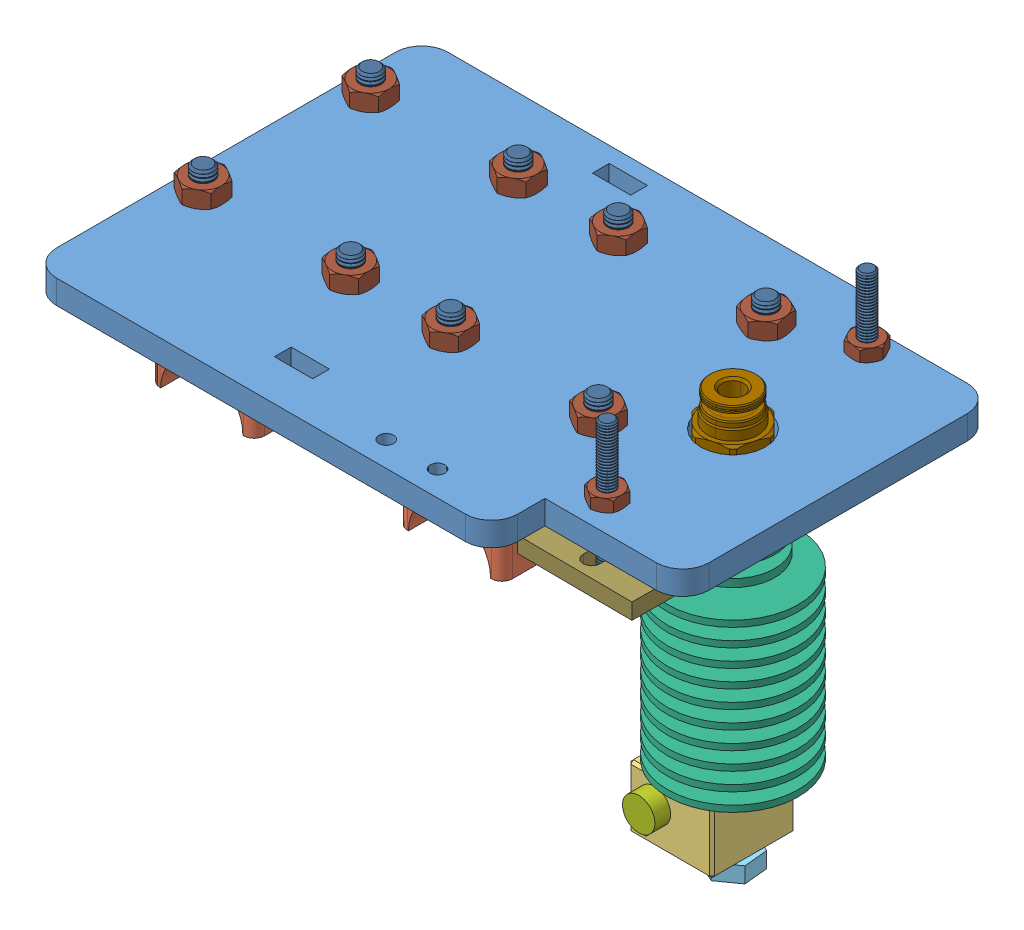
SolidWorks assembly print head assembly, configuration Default. Lengths in mm.
Overall size (114.36 87.96 74.73).
34 component instances, 12 part files, 60 mates.
Components (placement in the parent):
- mounting plate-1: mounting plate [Default] at (-11.5996 63.3996 119.5464) size (114.36 4.55 74.73)
- bearing housing-1: bearing housing [Default] at (17.6504 63.3996 74.0664) x (-1 0 0) z (0 0 1) size (38.1 17.15 28.7)
- bearing housing-2: bearing housing [Default] at (17.6504 63.3996 106.0664) x (-1 0 0) z (0 0 1) size (38.1 17.15 28.7)
- bearing housing-3: bearing housing [Default] at (64.9504 63.3996 74.0664) x (-1 0 0) z (0 0 1) size (38.1 17.15 28.7)
- bearing housing-4: bearing housing [Default] at (64.9504 63.3996 106.0664) x (-1 0 0) z (0 0 1) size (38.1 17.15 28.7)
- E3D-1: E3D [Default] at (78.8704 -0.8004 79.8564) x (-1 0 0) z (0 0 -1) size (28.79 69.7 28.79)
  - E3D Heat Block-1: E3D Heat Block [Default] at origin size (16 12 16)
  - E3D Heatbreak-1: E3D Heatbreak [Default] at (-4 19.55 0) x (-0.93266 0 -0.360757) z (-0.360757 0 0.93266) size (6 25.1 6)
  - E3D Nozzle-1: E3D Nozzle [Default] at (-4 -3.5 0) x (-0.097107 0 -0.995274) z (0.995274 0 -0.097107) size (9.24 12.5 8)
  - E3D Heatsink-1: E3D Heatsink [1.75 Bowden] at (-4 39.15 0) x (0.986263 0 -0.165183) z (0.165183 0 0.986263) size (25 50.1 25)
  - cartridge heater-1: cartridge heater [Default] at (3 7 0) x (0 0 1) z (-0.150948 -0.988542 0) size (32 6.2 6.2)
  - thermistor-1: thermistor [Default] at (-6 2 6.5) x (-0.997586 0.069447 0) z (-0.069447 -0.997586 0) size (2 13.25 2)
- PB156_1_8-1: PB156_1_8 [Default] at (82.8704 63.7223 79.8564) x (0 -1 0) z (0.258692 0 0.96596) size (19.6 12.3 13.69)
- socket head cap screw_am-6: socket head cap screw_am [B18.3.1M - 4 x 0.7 x 16 Hex SHCS -- 16SHX] at (69.0504 53.0996 59.7164) x (0 1 0) z (-0.973946 0 -0.226779) size (20 7 7)
- socket head cap screw_am-7: socket head cap screw_am [B18.3.1M - 4 x 0.7 x 16 Hex SHCS -- 16SHX] at (69.0504 53.0996 91.7164) x (0 1 0) z (0 0 1) size (20 7 7)
- socket head cap screw_am-8: socket head cap screw_am [B18.3.1M - 4 x 0.7 x 16 Hex SHCS -- 16SHX] at (21.7504 53.0996 91.7164) x (0 1 0) z (0 0 1) size (20 7 7)
- socket head cap screw_am-9: socket head cap screw_am [B18.3.1M - 4 x 0.7 x 16 Hex SHCS -- 16SHX] at (21.7504 53.0996 59.7164) x (0 1 0) z (0 0 1) size (20 7 7)
- socket head cap screw_am-10: socket head cap screw_am [B18.3.1M - 4 x 0.7 x 16 Hex SHCS -- 16SHX] at (40.8504 53.0996 91.7164) x (0 1 0) z (0 0 1) size (20 7 7)
- socket head cap screw_am-11: socket head cap screw_am [B18.3.1M - 4 x 0.7 x 16 Hex SHCS -- 16SHX] at (-6.4496 53.0996 91.7164) x (0 1 0) z (0 0 1) size (20 7 7)
- socket head cap screw_am-12: socket head cap screw_am [B18.3.1M - 4 x 0.7 x 16 Hex SHCS -- 16SHX] at (-6.4496 53.0996 59.7164) x (0 1 0) z (0 0 1) size (20 7 7)
- socket head cap screw_am-13: socket head cap screw_am [B18.3.1M - 4 x 0.7 x 16 Hex SHCS -- 16SHX] at (40.8504 53.0996 59.7164) x (0 1 0) z (0 0 1) size (20 7 7)
- hex nut style 1_am-1: hex nut style 1_am [B18.2.4.1M - Hex nut, Style 1,  M4 x 0.7 --D-N] at (69.0504 67.9496 59.7164) x (0.615546 0 0.788101) z (0 -1 0) size (7 8.08 3.2)
- hex nut style 1_am-2: hex nut style 1_am [B18.2.4.1M - Hex nut, Style 1,  M4 x 0.7 --D-N] at (69.0504 71.1496 91.7164) x (1 0 0) z (0 1 0) size (7 8.08 3.2)
- hex nut style 1_am-3: hex nut style 1_am [B18.2.4.1M - Hex nut, Style 1,  M4 x 0.7 --D-N] at (40.8504 71.1496 91.7164) x (1 0 0) z (0 1 0) size (7 8.08 3.2)
- hex nut style 1_am-4: hex nut style 1_am [B18.2.4.1M - Hex nut, Style 1,  M4 x 0.7 --D-N] at (21.7504 71.1496 91.7164) x (1 0 0) z (0 1 0) size (7 8.08 3.2)
- hex nut style 1_am-5: hex nut style 1_am [B18.2.4.1M - Hex nut, Style 1,  M4 x 0.7 --D-N] at (-6.4496 71.1496 91.7164) x (1 0 0) z (0 1 0) size (7 8.08 3.2)
- hex nut style 1_am-6: hex nut style 1_am [B18.2.4.1M - Hex nut, Style 1,  M4 x 0.7 --D-N] at (-6.4496 71.1496 59.7164) x (1 0 0) z (0 1 0) size (7 8.08 3.2)
- hex nut style 1_am-7: hex nut style 1_am [B18.2.4.1M - Hex nut, Style 1,  M4 x 0.7 --D-N] at (21.7504 71.1496 59.7164) x (1 0 0) z (0 1 0) size (7 8.08 3.2)
- hex nut style 1_am-8: hex nut style 1_am [B18.2.4.1M - Hex nut, Style 1,  M4 x 0.7 --D-N] at (40.8504 71.1496 59.7164) x (1 0 0) z (0 1 0) size (7 8.08 3.2)
- hotend bracket-1: hotend bracket [Default] at (93.6576 56.6596 109.9336) x (0.007083 0 -0.999975) z (0.999975 0 0.007083) size (60 3.04 22)
- socket head cap screw_am-14: socket head cap screw_am [B18.3.1M - 3 x 0.5 x 25 Hex SHCS -- 25SHX] at (82.8504 53.6596 54.2164) x (0 1 0) z (0 0 1) size (28 5.5 5.5)
- socket head cap screw_am-15: socket head cap screw_am [B18.3.1M - 3 x 0.5 x 25 Hex SHCS -- 25SHX] at (82.8504 53.6596 103.8564) x (0 1 0) z (-0.007083 0 0.999975) size (28 5.5 5.5)
- hex nut style 1_am-9: hex nut style 1_am [B18.2.4.1M - Hex nut, Style 1,  M3 x 0.5 --D-N] at (82.8504 67.9496 54.2164) x (0.837169 0 0.546944) z (0 -1 0) size (5.5 6.35 2.4)
- hex nut style 1_am-10: hex nut style 1_am [B18.2.4.1M - Hex nut, Style 1,  M3 x 0.5 --D-N] at (82.8504 70.3496 103.8564) x (1 0 0) z (0 1 0) size (5.5 6.35 2.4)
Mates (geometry in assembly coordinates):
- Coincident2: coincident anti-aligned: plane of mounting plate-1 through (97.7604 63.3996 104.3464) normal (0 -1 0); plane of bearing housing-2 through (17.6504 63.3996 106.0664) normal (0 1 0)
- Coincident3: coincident anti-aligned: plane of mounting plate-1 through (97.7604 63.3996 104.3464) normal (0 -1 0); plane of bearing housing-1 through (17.6504 63.3996 74.0664) normal (0 1 0)
- Coincident4: coincident anti-aligned: plane of mounting plate-1 through (97.7604 63.3996 104.3464) normal (0 -1 0); plane of bearing housing-4 through (64.9504 63.3996 106.0664) normal (0 1 0)
- Coincident5: coincident anti-aligned: plane of mounting plate-1 through (97.7604 63.3996 104.3464) normal (0 -1 0); plane of bearing housing-3 through (64.9504 63.3996 74.0664) normal (0 1 0)
- Concentric9: concentric anti-aligned: circle of mounting plate-1; cylinder of bearing housing-3 through (40.8504 57.0996 59.7164) axis (0 -1 0) radius 2.4
- Concentric10: concentric aligned: cylinder of mounting plate-1 through (40.8504 67.9496 91.7164) axis (0 -1 0) radius 2.15; cylinder of bearing housing-4 through (40.8504 57.0996 91.7164) axis (0 -1 0) radius 2.4
- Concentric11: concentric anti-aligned: circle of mounting plate-1; cylinder of bearing housing-4 through (69.0504 57.0996 91.7164) axis (0 -1 0) radius 2.4
- Concentric12: concentric anti-aligned: circle of mounting plate-1; circle of bearing housing-3
- Concentric13: concentric aligned: cylinder of mounting plate-1 through (21.7504 67.9496 91.7164) axis (0 -1 0) radius 2.15; circle of bearing housing-2
- Concentric14: concentric aligned: cylinder of mounting plate-1 through (-6.4496 67.9496 91.7164) axis (0 -1 0) radius 2.15; circle of bearing housing-2
- Concentric15: concentric aligned: cylinder of mounting plate-1 through (21.7504 67.9496 59.7164) axis (0 -1 0) radius 2.15; cylinder of bearing housing-1 through (21.7504 57.0996 59.7164) axis (0 -1 0) radius 2.4
- Concentric16: concentric aligned: cylinder of mounting plate-1 through (-6.4496 67.9496 59.7164) axis (0 -1 0) radius 2.15; cylinder of bearing housing-1 through (-6.4496 57.0996 59.7164) axis (0 -1 0) radius 2.4
- Concentric17: concentric aligned: cylinder of mounting plate-1 through (82.8704 67.9496 79.8564) axis (0 -1 0) radius 6.15; cylinder of E3D-1/E3D Heatsink-1 through (82.8704 13.2996 79.8564) axis (0 -1 0) radius 6
- Parallel1: parallel aligned: plane of mounting plate-1 through (102.7604 67.9496 104.3464) normal (1 0 0); plane of E3D-1/E3D Heat Block-1 through (86.8704 11.1996 71.8564) normal (1 0 0)
- Coincident7: coincident anti-aligned: plane of mounting plate-1 through (97.7604 63.3996 104.3464) normal (0 -1 0); plane of E3D-1/E3D Heatsink-1 through (78.0731 63.3996 80.6599) normal (0 1 0)
- Concentric18: concentric aligned: cylinder of E3D-1/E3D Heatsink-1 through (82.8704 13.2996 79.8564) axis (0 -1 0) radius 4.8641; cone of PB156_1_8-1 through (82.8704 63.7223 79.8564) axis (0 -1 0)
- Coincident8: coincident: circle of E3D-1/E3D Heatsink-1; cone of PB156_1_8-1 through (82.8704 64.2405 79.8564) axis (0 -1 0)
- Concentric22: concentric aligned: cylinder of bearing housing-4 through (69.0504 57.0996 91.7164) axis (0 -1 0) radius 2.4; cylinder of socket head cap screw_am-7 through (69.0504 21.3496 91.7164) axis (0 -1 0) radius 3.5
- Coincident12: coincident anti-aligned: plane of bearing housing-4 through (68.2397 57.0996 85.6864) normal (0 -1 0); plane of socket head cap screw_am-7 through (65.5504 57.0996 91.7164) normal (0 1 0)
- Concentric23: concentric aligned: cylinder of bearing housing-2 through (21.7504 57.0996 91.7164) axis (0 -1 0) radius 2.4; cylinder of socket head cap screw_am-8 through (21.7504 21.3496 91.7164) axis (0 -1 0) radius 3.5
- Coincident13: coincident anti-aligned: plane of bearing housing-2 through (20.9397 57.0996 85.6864) normal (0 -1 0); plane of socket head cap screw_am-8 through (18.2504 57.0996 91.7164) normal (0 1 0)
- Concentric241: concentric aligned: cylinder of bearing housing-1 through (21.7504 57.0996 59.7164) axis (0 -1 0) radius 2.4; cylinder of socket head cap screw_am-9 through (21.7504 21.3496 59.7164) axis (0 -1 0) radius 3.5
- Coincident141: coincident anti-aligned: plane of bearing housing-1 through (20.9397 57.0996 53.6864) normal (0 -1 0); plane of socket head cap screw_am-9 through (18.2504 57.0996 59.7164) normal (0 1 0)
- Concentric25: concentric aligned: cylinder of bearing housing-4 through (40.8504 57.0996 91.7164) axis (0 -1 0) radius 2.4; cylinder of socket head cap screw_am-10 through (40.8504 21.3496 91.7164) axis (0 -1 0) radius 3.5
- Coincident15: coincident anti-aligned: plane of bearing housing-4 through (41.6611 57.0996 85.6864) normal (0 -1 0); plane of socket head cap screw_am-10 through (37.3504 57.0996 91.7164) normal (0 1 0)
- Concentric26: concentric aligned: cylinder of bearing housing-2 through (-6.4496 57.0996 91.7164) axis (0 -1 0) radius 2.4; cylinder of socket head cap screw_am-11 through (-6.4496 21.3496 91.7164) axis (0 -1 0) radius 3.5
- Coincident16: coincident anti-aligned: plane of bearing housing-2 through (-5.6389 57.0996 85.6864) normal (0 -1 0); plane of socket head cap screw_am-11 through (-9.9496 57.0996 91.7164) normal (0 1 0)
- Concentric27: concentric aligned: cylinder of bearing housing-1 through (-6.4496 57.0996 59.7164) axis (0 -1 0) radius 2.4; cylinder of socket head cap screw_am-12 through (-6.4496 21.3496 59.7164) axis (0 -1 0) radius 3.5
- Coincident17: coincident anti-aligned: plane of bearing housing-1 through (-5.6389 57.0996 53.6864) normal (0 -1 0); plane of socket head cap screw_am-12 through (-9.9496 57.0996 59.7164) normal (0 1 0)
- Concentric28: concentric aligned: cylinder of bearing housing-3 through (40.8504 57.0996 59.7164) axis (0 -1 0) radius 2.4; cylinder of socket head cap screw_am-13 through (40.8504 21.3496 59.7164) axis (0 -1 0) radius 3.5
- Coincident18: coincident anti-aligned: plane of bearing housing-3 through (41.6611 57.0996 53.6864) normal (0 -1 0); plane of socket head cap screw_am-13 through (37.3504 57.0996 59.7164) normal (0 1 0)
- Concentric29: concentric aligned: circle of bearing housing-3; circle of socket head cap screw_am-6
- Coincident19: coincident anti-aligned: plane of bearing housing-3 through (68.2397 57.0996 53.6864) normal (0 -1 0); plane of socket head cap screw_am-6 through (69.8441 57.0996 56.3076) normal (0 1 0)
- Concentric30: concentric anti-aligned: cylinder of mounting plate-1 through (69.0504 67.9496 91.7164) axis (0 -1 0) radius 2.15; cylinder of hex nut style 1_am-2 through (69.0504 46.1121 91.7164) axis (0 1 0) radius 2
- Coincident20: coincident anti-aligned: plane of mounting plate-1 through (97.7604 67.9496 104.3464) normal (0 1 0); plane of hex nut style 1_am-2 through (69.0504 67.9496 87.675) normal (0 -1 0)
- Concentric31: concentric anti-aligned: cylinder of mounting plate-1 through (40.8504 67.9496 91.7164) axis (0 -1 0) radius 2.15; cylinder of hex nut style 1_am-3 through (40.8504 46.1121 91.7164) axis (0 1 0) radius 2
- Coincident21: coincident anti-aligned: plane of mounting plate-1 through (97.7604 67.9496 104.3464) normal (0 1 0); plane of hex nut style 1_am-3 through (40.8504 67.9496 87.675) normal (0 -1 0)
- Concentric32: concentric anti-aligned: cylinder of mounting plate-1 through (21.7504 67.9496 91.7164) axis (0 -1 0) radius 2.15; cylinder of hex nut style 1_am-4 through (21.7504 46.1121 91.7164) axis (0 1 0) radius 2
- Coincident22: coincident anti-aligned: plane of mounting plate-1 through (97.7604 67.9496 104.3464) normal (0 1 0); plane of hex nut style 1_am-4 through (21.7504 67.9496 87.675) normal (0 -1 0)
- Concentric33: concentric anti-aligned: cylinder of mounting plate-1 through (-6.4496 67.9496 91.7164) axis (0 -1 0) radius 2.15; cylinder of hex nut style 1_am-5 through (-6.4496 46.1121 91.7164) axis (0 1 0) radius 2
- Coincident23: coincident anti-aligned: plane of mounting plate-1 through (97.7604 67.9496 104.3464) normal (0 1 0); plane of hex nut style 1_am-5 through (-6.4496 67.9496 87.675) normal (0 -1 0)
- Concentric341: concentric anti-aligned: cylinder of mounting plate-1 through (-6.4496 67.9496 59.7164) axis (0 -1 0) radius 2.15; cylinder of hex nut style 1_am-6 through (-6.4496 46.1121 59.7164) axis (0 1 0) radius 2
- Coincident241: coincident anti-aligned: plane of mounting plate-1 through (97.7604 67.9496 104.3464) normal (0 1 0); plane of hex nut style 1_am-6 through (-6.4496 67.9496 55.675) normal (0 -1 0)
- Concentric35: concentric anti-aligned: cylinder of mounting plate-1 through (21.7504 67.9496 59.7164) axis (0 -1 0) radius 2.15; cylinder of hex nut style 1_am-7 through (21.7504 46.1121 59.7164) axis (0 1 0) radius 2
- Coincident25: coincident anti-aligned: plane of mounting plate-1 through (97.7604 67.9496 104.3464) normal (0 1 0); plane of hex nut style 1_am-7 through (21.7504 67.9496 55.675) normal (0 -1 0)
- Concentric36: concentric anti-aligned: cylinder of mounting plate-1 through (40.8504 67.9496 59.7164) axis (0 -1 0) radius 2.15; cylinder of hex nut style 1_am-8 through (40.8504 46.1121 59.7164) axis (0 1 0) radius 2
- Coincident26: coincident anti-aligned: plane of mounting plate-1 through (97.7604 67.9496 104.3464) normal (0 1 0); plane of hex nut style 1_am-8 through (40.8504 67.9496 55.675) normal (0 -1 0)
- Concentric37: concentric anti-aligned: circle of mounting plate-1; cylinder of hex nut style 1_am-1 through (69.0504 71.1496 59.7164) axis (0 -1 0) radius 1.65
- Coincident27: coincident anti-aligned: plane of mounting plate-1 through (97.7604 67.9496 104.3464) normal (0 1 0); plane of hex nut style 1_am-1 through (65.8653 67.9496 62.2041) normal (0 -1 0)
- Concentric38: concentric aligned: cylinder of E3D-1/E3D Heatsink-1 through (82.8704 13.2996 79.8564) axis (0 -1 0) radius 6; cylinder of hotend bracket-1 through (82.8704 59.6996 79.8564) axis (0 -1 0) radius 6
- Coincident28: coincident anti-aligned: plane of E3D-1/E3D Heatsink-1 through (76.9528 59.6996 80.8475) normal (0 -1 0); plane of hotend bracket-1 through (82.8704 59.6996 79.8564) normal (0 1 0)
- Tangent2: tangent anti-aligned: cylinder of mounting plate-1 through (82.8504 67.9496 103.8564) axis (0 -1 0) radius 1.75; plane of hotend bracket-1 through (81.0806 59.6996 106.6444) normal (0.999975 0 0.007083)
- Coincident30: coincident anti-aligned: plane of hotend bracket-1 through (82.8704 56.6596 79.8564) normal (0 -1 0); plane of socket head cap screw_am-15 through (80.1005 56.6596 103.837) normal (0 1 0)
- Concentric39: concentric aligned: cylinder of mounting plate-1 through (82.8504 67.9496 103.8564) axis (0 -1 0) radius 1.75; cylinder of socket head cap screw_am-15 through (82.8504 21.9096 103.8564) axis (0 -1 0) radius 2.75
- Coincident31: coincident anti-aligned: plane of hotend bracket-1 through (82.8704 56.6596 79.8564) normal (0 -1 0); plane of socket head cap screw_am-14 through (80.1004 56.6596 54.2164) normal (0 1 0)
- Concentric40: concentric aligned: cylinder of mounting plate-1 through (82.8504 67.9496 54.2164) axis (0 -1 0) radius 1.75; cylinder of socket head cap screw_am-14 through (82.8504 21.9096 54.2164) axis (0 -1 0) radius 2.75
- Concentric41: concentric anti-aligned: cylinder of mounting plate-1 through (82.8504 67.9496 103.8564) axis (0 -1 0) radius 1.75; cylinder of hex nut style 1_am-10 through (82.8504 45.3121 103.8564) axis (0 1 0) radius 1.5
- Coincident32: coincident anti-aligned: plane of mounting plate-1 through (97.7604 67.9496 104.3464) normal (0 1 0); plane of hex nut style 1_am-10 through (82.8504 67.9496 100.681) normal (0 -1 0)
- Coincident33: coincident anti-aligned: plane of mounting plate-1 through (97.7604 67.9496 104.3464) normal (0 1 0); plane of hex nut style 1_am-9 through (81.1136 67.9496 56.8748) normal (0 -1 0)
- Concentric42: concentric aligned: circle of socket head cap screw_am-14; circle of hex nut style 1_am-9
